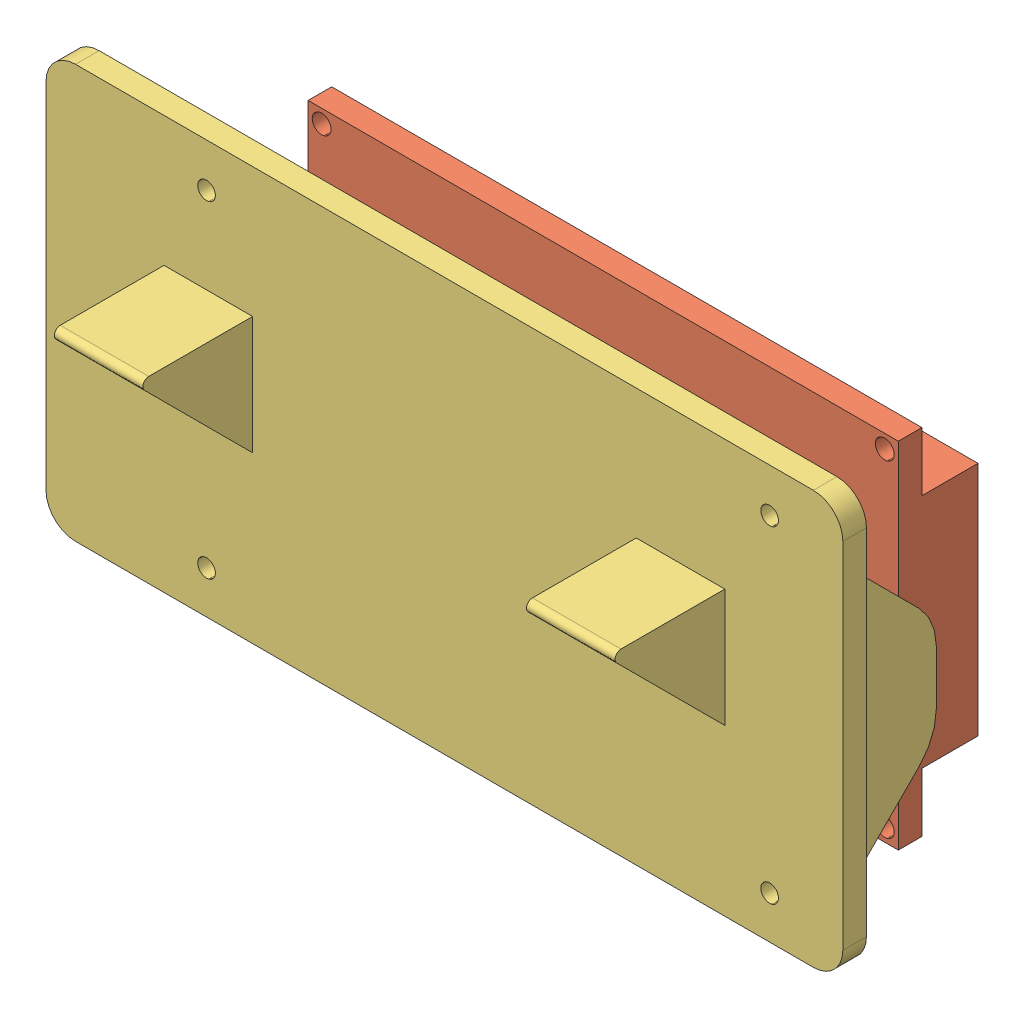
SolidWorks assembly A screen, configuration Défaut. Lengths in mm.
Overall size (135.1 70.1 58.09).
5 component instances, 4 part files, 7 mates.
Components (placement in the parent):
- Screen support v1.1-1: Screen support v1.1 [Défaut] at (-19.5509 -0.7603 130.5) size (135 70 4)
- A screen button-1: A screen button [Défaut] at (-72.5032 1.4324 156.5) x (0 -1 0) z (0 0 -1) size (60 117 25)
  - button-1: button [Défaut] at (-0.3073 1.0477 12.5) size (15 11 25)
  - screen-1: screen [Défaut] at (-27.8073 -10.4523 12.5) x (0 -1 0) z (0 0 1) size (100 60 13.5)
- support screen back-2: support screen back [Défaut] at (-19.4509 -0.6603 163.5) x (-1 0 0) z (0 0 -1) size (135 70 31.63)
Mates (geometry in assembly coordinates):
- Coïncidente1: coincident anti-aligned: plane of Screen support v1.1-1 through (-19.5509 -0.7603 149.5) normal (0 0 1); plane of ? through (-17.0509 -0.7603 149.5) normal (0 0 -1)
- Coïncidente2: coincident aligned: plane of Screen support v1.1-1 through (47.9491 34.2397 134.5) normal (1 0 0); plane of ? through (47.9491 34.2397 153.5) normal (1 0 0)
- Coïncidente3: coincident aligned: plane of Screen support v1.1-1 through (-87.0509 -35.7603 134.5) normal (0 -1 0); plane of ? through (-87.0509 -35.7603 153.5) normal (0 -1 0)
- Coïncidente9: coincident anti-aligned: plane of Screen support v1.1-1 through (-62.0509 19.7397 134.5) normal (1 0 0); plane of A screen button-1/screen-1 through (-62.0509 29.2397 140) normal (-1 0 0)
- Distance1: distance = 0.5 mm anti-aligned: plane of A screen button-1/screen-1 through (-62.0509 19.2397 130.5) normal (0 1 0); plane of Screen support v1.1-1 through (-62.0509 19.7397 134.5) normal (0 -1 0)
- Coïncidente10: coincident aligned: plane of Screen support v1.1-1 through (-82.0509 29.2397 130.5) normal (0 0 -1); plane of A screen button-1/screen-1 through (-62.0509 29.2397 130.5) normal (0 0 -1)
- Coïncidente13: coincident anti-aligned: plane of Screen support v1.1-1 through (-82.0509 -30.7603 159.5) normal (0 0 1); plane of support screen back-2 through (43.0491 -30.6603 159.5) normal (0 0 -1)
